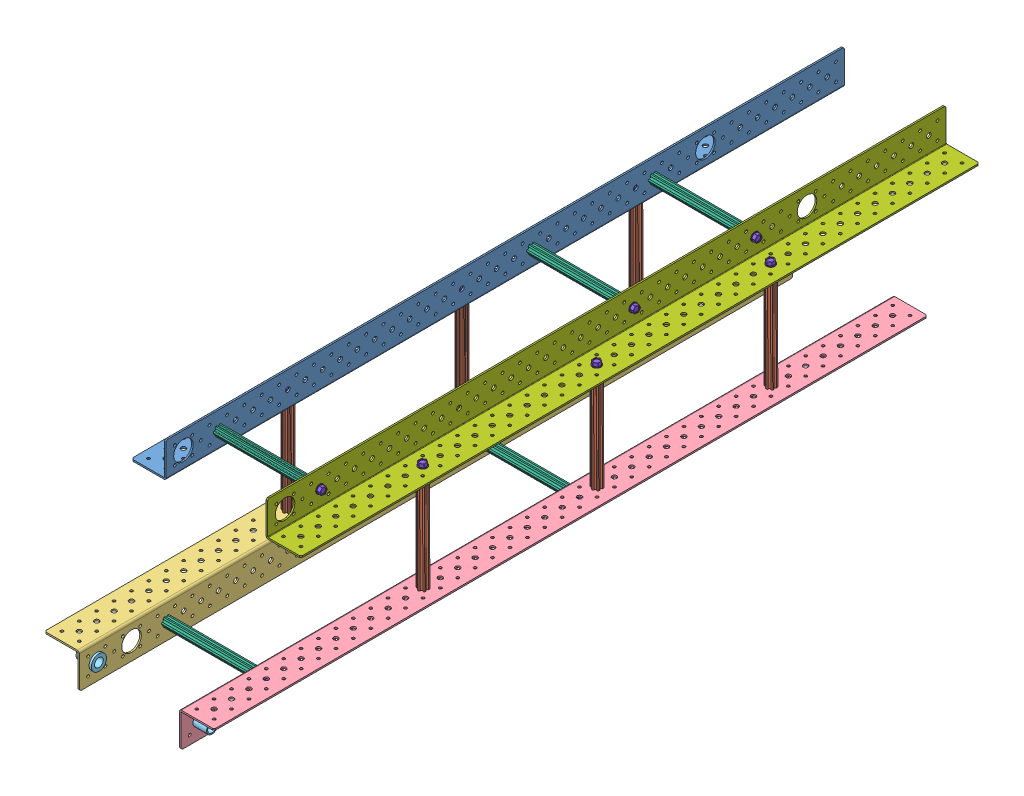
SolidWorks assembly intakePIPE, configuration Default. Lengths in mm.
Overall size (247.65 256.5 1117.26).
39 component instances, 8 part files, 96 mates.
Components (placement in the parent):
- 32inchMODIFIED-2: 32inchMODIFIED [Default] at (206.0968 622.2033 557.3996) x (0 0.999997 0.002241) z (0 -0.002241 0.999997) size (50.8 50.8 990.6)
- am-churro 500 churro tube MODIFIED-1: am-churro 500 churro tube MODIFIED [Default] at (180.6968 317.3187 594.8165) x (0 -0.002241 0.999997) z (0 0.999997 0.002241) size (14.66 12.7 152.4)
- am-churro 500 churro tube MODIFIED-2: am-churro 500 churro tube MODIFIED [Default] at (180.6968 773.3792 1103.8398) x (0 -0.002241 0.999997) z (0 -0.999997 -0.002241) size (14.66 12.7 152.4)
- am-churro 500 churro tube MODIFIED-3: am-churro 500 churro tube MODIFIED [Default] at (377.5468 773.3792 1103.8398) x (0.866025 0.00112 -0.499999) z (0 -0.999997 -0.002241) size (14.66 12.7 152.4)
- am-churro 500 churro tube MODIFIED-4: am-churro 500 churro tube MODIFIED [Default] at (377.5468 774.5176 595.8411) x (0.866025 0.00112 -0.499999) z (0 -0.999997 -0.002241) size (14.66 12.7 152.4)
- 32inchMODIFIED_BOTTOM-1: 32inchMODIFIED_BOTTOM [Default] at (206.0968 468.4946 1141.2567) x (0 -0.999997 -0.002241) z (0 0.002241 -0.999997) size (50.8 50.8 1041.4)
- 32inchMODIFIED_BOTTOM_2-1: 32inchMODIFIED_BOTTOM_2 [Default] at (352.1468 469.5191 684.0578) x (0 -0.999997 -0.002241) z (0 -0.002241 0.999997) size (50.8 50.8 1041.4)
- bushing1-1: bushing1 [Default] at (209.2718 442.497 1407.8991) x (0 0.579882 -0.8147) z (-1 0 0) size (22.26 22.26 25.4)
- bushing1-2: bushing1 [Default] at (348.9718 442.497 1407.8991) x (0 0.875683 0.482886) z (1 0 0) size (22.26 22.26 25.4)
- am-churro 500 churro tube MODIFIED-5: am-churro 500 churro tube MODIFIED [Default] at (377.5468 773.9484 849.8404) x (0 -0.002241 0.999997) z (0 -0.999997 -0.002241) size (14.66 12.7 152.4)
- am-churro 500 churro tube MODIFIED-6: am-churro 500 churro tube MODIFIED [Default] at (180.6968 773.9484 849.8404) x (0.866025 -0.00112 0.499999) z (0 -0.999997 -0.002241) size (14.66 12.7 152.4)
- am-churro 500 churro tube MODIFIED_5_5-1: am-churro 500 churro tube MODIFIED_5_5 [Default] at (47.3468 646.0949 1230.5549) x (0 0.864903 0.501939) z (1 0 0) size (14.66 12.7 146.05)
- am-churro 500 churro tube MODIFIED_5_5-2: am-churro 500 churro tube MODIFIED_5_5 [Default] at (47.3468 443.7492 849.1005) x (0 0.002241 -0.999997) z (1 0 0) size (14.66 12.7 146.05)
- am-churro 500 churro tube MODIFIED_5_5-3: am-churro 500 churro tube MODIFIED_5_5 [Default] at (510.8968 442.7247 1306.2993) x (0 0.002241 -0.999997) z (-1 0 0) size (14.66 12.7 146.05)
- 32inchMODIFIED_TOP2-3: 32inchMODIFIED_TOP2 [Default] at (352.1468 620.7804 1192.398) x (0 0.999997 0.002241) z (0 0.002241 -0.999997) size (50.8 50.8 990.6)
- am-churro 500 churro tube MODIFIED_5_5-4: am-churro 500 churro tube MODIFIED_5_5 [Default] at (47.3468 647.5179 595.5565) x (0 0.002241 -0.999997) z (1 0 0) size (14.66 12.7 146.05)
- am-churro 500 churro tube MODIFIED_5_5-5: am-churro 500 churro tube MODIFIED_5_5 [Default] at (47.3468 647.1195 773.356) x (0 0 -1) z (1 0 0) size (14.66 12.7 146.05)
- FHTS 0.25-20-0.75-1: FHTS 0.25-20-0.75 [FHTS 0.25-20-G-0.75-C] at (354.4328 647.5179 595.5565) x (-1 0 0) z (0 0.924225 0.381849) size (19.05 6.35 6.35)
- FHTS 0.25-20-0.75-2: FHTS 0.25-20-0.75 [FHTS 0.25-20-G-0.75-C] at (377.5468 624.4039 595.5047) x (0 -0.999997 -0.002241) z (0.002241 -0.002241 0.999995) size (19.05 6.35 6.35)
- FHTS 0.25-20-0.75-3: FHTS 0.25-20-0.75 [FHTS 0.25-20-G-0.75-C] at (354.4328 647.1195 773.356) x (-1 0 0) z (0 0.924225 0.381849) size (19.05 6.35 6.35)
- FHTS 0.25-20-0.75-4: FHTS 0.25-20-0.75 [FHTS 0.25-20-G-0.75-C] at (377.5468 623.8348 849.504) x (0 -0.999997 -0.002241) z (0.002241 -0.002241 0.999995) size (19.05 6.35 6.35)
- FHTS 0.25-20-0.75-5: FHTS 0.25-20-0.75 [FHTS 0.25-20-G-0.75-C] at (354.4328 646.0949 1230.5549) x (-1 0 0) z (0 0.924225 0.381849) size (19.05 6.35 6.35)
- FHTS 0.25-20-0.75-6: FHTS 0.25-20-0.75 [FHTS 0.25-20-G-0.75-C] at (377.5468 623.2656 1103.5034) x (0 -0.999997 -0.002241) z (0.002241 -0.002241 0.999995) size (19.05 6.35 6.35)
- FHTS 0.25-20-0.75-7: FHTS 0.25-20-0.75 [FHTS 0.25-20-G-0.75-C] at (354.4328 442.7247 1306.2993) x (-1 0 0) z (0 0.924225 0.381849) size (19.05 6.35 6.35)
- FHTS 0.25-20-0.75-8: FHTS 0.25-20-0.75 [FHTS 0.25-20-G-0.75-C] at (377.5468 466.294 1103.1516) x (0 0.999997 0.002241) z (-0.002241 -0.002241 0.999995) size (19.05 6.35 6.35)
- FHTS 0.25-20-0.75-9: FHTS 0.25-20-0.75 [FHTS 0.25-20-G-0.75-C] at (377.5468 466.8632 849.1523) x (0 0.999997 0.002241) z (-0.002241 -0.002241 0.999995) size (19.05 6.35 6.35)
- FHTS 0.25-20-0.75-10: FHTS 0.25-20-0.75 [FHTS 0.25-20-G-0.75-C] at (354.4328 443.7492 849.1005) x (-1 0 0) z (0 0.924225 0.381849) size (19.05 6.35 6.35)
- FHTS 0.25-20-0.75-11: FHTS 0.25-20-0.75 [FHTS 0.25-20-G-0.75-C] at (377.5468 467.4323 595.1529) x (0 0.999997 0.002241) z (-0.002241 -0.002241 0.999995) size (19.05 6.35 6.35)
- FHTS 0.25-20-0.75-12: FHTS 0.25-20-0.75 [FHTS 0.25-20-G-0.75-C] at (180.6968 466.294 1103.1516) x (0 0.999997 0.002241) z (-0.002241 -0.002241 0.999995) size (19.05 6.35 6.35)
- FHTS 0.25-20-0.75-13: FHTS 0.25-20-0.75 [FHTS 0.25-20-G-0.75-C] at (203.8108 442.7247 1306.2993) size (19.05 6.35 6.35)
- FHTS 0.25-20-0.75-14: FHTS 0.25-20-0.75 [FHTS 0.25-20-G-0.75-C] at (203.8108 443.7492 849.1005) size (19.05 6.35 6.35)
- FHTS 0.25-20-0.75-15: FHTS 0.25-20-0.75 [FHTS 0.25-20-G-0.75-C] at (180.6968 466.8632 849.1523) x (0 0.999997 0.002241) z (-0.002241 -0.002241 0.999995) size (19.05 6.35 6.35)
- FHTS 0.25-20-0.75-16: FHTS 0.25-20-0.75 [FHTS 0.25-20-G-0.75-C] at (180.6968 467.4323 595.1529) x (0 0.999997 0.002241) z (-0.002241 -0.002241 0.999995) size (19.05 6.35 6.35)
- FHTS 0.25-20-0.75-17: FHTS 0.25-20-0.75 [FHTS 0.25-20-G-0.75-C] at (203.8108 646.0949 1230.5549) size (19.05 6.35 6.35)
- FHTS 0.25-20-0.75-18: FHTS 0.25-20-0.75 [FHTS 0.25-20-G-0.75-C] at (180.6968 623.2656 1103.5034) x (0 -0.999997 -0.002241) z (0.002241 -0.002241 0.999995) size (19.05 6.35 6.35)
- FHTS 0.25-20-0.75-19: FHTS 0.25-20-0.75 [FHTS 0.25-20-G-0.75-C] at (180.6968 623.8348 849.504) x (0 -0.999997 -0.002241) z (0.002241 -0.002241 0.999995) size (19.05 6.35 6.35)
- FHTS 0.25-20-0.75-20: FHTS 0.25-20-0.75 [FHTS 0.25-20-G-0.75-C] at (203.8108 647.1195 773.356) size (19.05 6.35 6.35)
- FHTS 0.25-20-0.75-21: FHTS 0.25-20-0.75 [FHTS 0.25-20-G-0.75-C] at (180.6968 624.4039 595.5047) x (0 -0.999997 -0.002241) z (0.002241 -0.002241 0.999995) size (19.05 6.35 6.35)
- FHTS 0.25-20-0.75-22: FHTS 0.25-20-0.75 [FHTS 0.25-20-G-0.75-C] at (203.8108 647.5179 595.5565) size (19.05 6.35 6.35)
Mates (geometry in assembly coordinates):
- Parallel3: parallel anti-aligned: plane of 32inchMODIFIED_BOTTOM-1 through (206.0968 466.8155 1890.5548) normal (1 0 0); plane of 32inchMODIFIED_BOTTOM_2-1 through (352.1468 471.1982 -65.2403) normal (-1 0 0)
- Parallel4: parallel anti-aligned: plane of 32inchMODIFIED-2 through (206.0968 623.8824 -191.8985) normal (0 -0.999997 -0.002241); plane of 32inchMODIFIED_BOTTOM-1 through (206.0968 466.8155 1890.5548) normal (0 0.999997 0.002241)
- Coincident509: coincident anti-aligned: plane of 32inchMODIFIED-2 through (206.0968 623.8824 -191.8985) normal (0 -0.999997 -0.002241); plane of am-churro 500 churro tube MODIFIED-1 through (183.8718 622.1056 600.9988) normal (0 0.999997 0.002241)
- Coincident510: coincident anti-aligned: plane of am-churro 500 churro tube MODIFIED-1 through (171.8068 469.7183 595.158) normal (0 -0.999997 -0.002241); plane of 32inchMODIFIED_BOTTOM-1 through (206.0968 466.8155 1890.5548) normal (0 0.999997 0.002241)
- Coincident512: coincident anti-aligned: plane of am-churro 500 churro tube MODIFIED-4 through (383.8968 469.7183 595.158) normal (0 -0.999997 -0.002241); plane of 32inchMODIFIED_BOTTOM_2-1 through (352.1468 471.1982 -65.2403) normal (0 0.999997 0.002241)
- Parallel6: parallel aligned: plane of am-churro 500 churro tube MODIFIED-1 through (174.3468 622.1144 597.087) normal (-1 0 0); plane of 32inchMODIFIED_BOTTOM-1 through (155.2968 466.8155 1890.5548) normal (-1 0 0)
- Parallel7: parallel aligned: plane of am-churro 500 churro tube MODIFIED-4 through (383.8968 469.7148 596.7455) normal (1 0 0); plane of 32inchMODIFIED_BOTTOM_2-1 through (402.9468 471.1982 -65.2403) normal (1 0 0)
- Concentric513: concentric anti-aligned: cylinder of 32inchMODIFIED_BOTTOM-1 through (246.508 442.6109 1357.0992) axis (-1 0 0) radius 14.2875; cylinder of 32inchMODIFIED_BOTTOM_2-1 through (311.7357 442.6109 1357.0992) axis (1 0 0) radius 14.2875
- Concentric514: concentric anti-aligned: cylinder of 32inchMODIFIED_BOTTOM_2-1 through (311.7357 442.497 1407.8991) axis (1 0 0) radius 7.9693; cylinder of bushing1-2 through (374.3718 442.497 1407.8991) axis (-1 0 0) radius 7.9693
- Coincident518: coincident anti-aligned: plane of 32inchMODIFIED_BOTTOM_2-1 through (352.1468 471.1982 -65.2403) normal (-1 0 0); plane of bushing1-2 through (352.1468 442.497 1407.8991) normal (1 0 0)
- Concentric515: concentric anti-aligned: cylinder of 32inchMODIFIED_BOTTOM-1 through (246.508 442.497 1407.8991) axis (-1 0 0) radius 7.9693; cylinder of bushing1-1 through (183.8718 442.497 1407.8991) axis (1 0 0) radius 7.9693
- Coincident519: coincident anti-aligned: plane of 32inchMODIFIED_BOTTOM-1 through (206.0968 466.8155 1890.5548) normal (1 0 0); plane of bushing1-1 through (206.0968 442.497 1407.8991) normal (-1 0 0)
- Coincident520: coincident anti-aligned: plane of am-churro 500 churro tube MODIFIED-3 through (383.8968 468.58 1103.1568) normal (0 -0.999997 -0.002241); plane of 32inchMODIFIED_BOTTOM_2-1 through (352.1468 471.1982 -65.2403) normal (0 0.999997 0.002241)
- Coincident522: coincident anti-aligned: plane of am-churro 500 churro tube MODIFIED-2 through (177.5218 468.5676 1108.656) normal (0 -0.999997 -0.002241); plane of 32inchMODIFIED_BOTTOM-1 through (206.0968 466.8155 1890.5548) normal (0 0.999997 0.002241)
- Coincident523: coincident anti-aligned: plane of 32inchMODIFIED-2 through (206.0968 623.8824 -191.8985) normal (0 -0.999997 -0.002241); plane of am-churro 500 churro tube MODIFIED-2 through (189.5868 620.9796 1103.4983) normal (0 0.999997 0.002241)
- Coincident524: coincident anti-aligned: plane of 32inchMODIFIED_BOTTOM-1 through (206.0968 466.8155 1890.5548) normal (0 0.999997 0.002241); plane of am-churro 500 churro tube MODIFIED-6 through (183.8718 469.1368 854.6567) normal (0 -0.999997 -0.002241)
- Coincident525: coincident anti-aligned: plane of 32inchMODIFIED-2 through (206.0968 623.8824 -191.8985) normal (0 -0.999997 -0.002241); plane of am-churro 500 churro tube MODIFIED-6 through (185.1418 621.566 841.8) normal (0 0.999997 0.002241)
- Parallel8: parallel aligned: plane of 32inchMODIFIED_BOTTOM-1 through (155.2968 466.8155 1890.5548) normal (-1 0 0); plane of am-churro 500 churro tube MODIFIED-6 through (174.3468 469.1409 852.8236) normal (-1 0 0)
- Parallel9: parallel aligned: plane of am-churro 500 churro tube MODIFIED-2 through (174.3468 468.5718 1106.8229) normal (-1 0 0); plane of 32inchMODIFIED_BOTTOM-1 through (155.2968 466.8155 1890.5548) normal (-1 0 0)
- Parallel10: parallel aligned: plane of am-churro 500 churro tube MODIFIED-3 through (383.8968 468.5882 1099.4906) normal (1 0 0); plane of 32inchMODIFIED_BOTTOM_2-1 through (402.9468 471.1982 -65.2403) normal (1 0 0)
- Coincident529: coincident anti-aligned: plane of 32inchMODIFIED_BOTTOM_2-1 through (352.1468 471.1982 -65.2403) normal (-1 0 0); plane of am-churro 500 churro tube MODIFIED_5_5-3 through (352.1468 451.6147 1306.3193) normal (1 0 0)
- Coincident530: coincident anti-aligned: plane of 32inchMODIFIED_BOTTOM-1 through (206.0968 466.8155 1890.5548) normal (1 0 0); plane of am-churro 500 churro tube MODIFIED_5_5-3 through (206.0968 439.562 1300.793) normal (-1 0 0)
- Parallel11: parallel aligned: plane of 32inchMODIFIED_BOTTOM-1 through (203.8108 416.0157 1890.441) normal (0 -0.999997 -0.002241); plane of am-churro 500 churro tube MODIFIED_5_5-3 through (206.0968 436.3829 1302.6189) normal (0 -0.999997 -0.002241)
- Coincident532: coincident anti-aligned: plane of 32inchMODIFIED_BOTTOM_2-1 through (352.1468 471.1982 -65.2403) normal (0 0.999997 0.002241); plane of am-churro 500 churro tube MODIFIED-5 through (374.3718 469.1368 854.6567) normal (0 -0.999997 -0.002241)
- Parallel12: parallel aligned: plane of 32inchMODIFIED_BOTTOM_2-1 through (402.9468 471.1982 -65.2403) normal (1 0 0); plane of am-churro 500 churro tube MODIFIED-5 through (383.8968 469.1574 845.4912) normal (1 0 0)
- Coincident535: coincident anti-aligned: plane of 32inchMODIFIED-2 through (206.0968 623.8824 -191.8985) normal (1 0 0); plane of am-churro 500 churro tube MODIFIED_5_5-1 through (206.0968 650.5572 1222.8659) normal (-1 0 0)
- Coincident536: coincident anti-aligned: plane of 32inchMODIFIED_BOTTOM-1 through (206.0968 466.8155 1890.5548) normal (1 0 0); plane of am-churro 500 churro tube MODIFIED_5_5-2 through (206.0968 434.8592 849.0806) normal (-1 0 0)
- Coincident537: coincident anti-aligned: plane of 32inchMODIFIED_BOTTOM_2-1 through (352.1468 471.1982 -65.2403) normal (-1 0 0); plane of am-churro 500 churro tube MODIFIED_5_5-2 through (352.1468 446.9365 843.6084) normal (1 0 0)
- Parallel13: parallel aligned: plane of 32inchMODIFIED_BOTTOM_2-1 through (352.1468 471.1982 -65.2403) normal (0 0.999997 0.002241); plane of am-churro 500 churro tube MODIFIED_5_5-2 through (352.1468 450.1074 845.4486) normal (0 0.999997 0.002241)
- Concentric530: concentric anti-aligned: cylinder of 32inchMODIFIED-2 through (246.508 647.6886 519.3567) axis (-1 0 0) radius 14.2875; cylinder of 32inchMODIFIED_TOP2-3 through (349.3528 647.6886 519.3567) axis (1 0 0) radius 14.2875
- Coincident5553: coincident anti-aligned: plane of am-churro 500 churro tube MODIFIED-5 through (386.4368 621.5488 849.4989) normal (0 0.999997 0.002241); plane of 32inchMODIFIED_TOP2-3 through (352.1468 619.1013 1941.6962) normal (0 -0.999997 -0.002241)
- Concentric5533: concentric anti-aligned: cylinder of 32inchMODIFIED_BOTTOM-1 through (246.508 444.4891 518.9013) axis (-1 0 0) radius 14.2875; cylinder of 32inchMODIFIED_BOTTOM_2-1 through (311.7357 444.4891 518.9013) axis (1 0 0) radius 14.2875
- Parallel15: parallel aligned: plane of 32inchMODIFIED-2 through (203.8108 674.6822 -191.7846) normal (0 0.999997 0.002241); plane of am-churro 500 churro tube MODIFIED_5_5-4 through (352.1468 653.8643 597.1582) normal (0 0.999997 0.002241)
- Coincident5554: coincident aligned: plane of 32inchMODIFIED_BOTTOM_2-1 through (352.1468 471.1982 -65.2403) normal (-1 0 0); plane of 32inchMODIFIED_TOP2-3 through (352.1468 619.1013 1941.6962) normal (-1 0 0)
- Coincident5555: coincident aligned: plane of 32inchMODIFIED-2 through (206.0968 623.8824 -191.8985) normal (0 -0.999997 -0.002241); plane of 32inchMODIFIED_TOP2-3 through (352.1468 619.1013 1941.6962) normal (0 -0.999997 -0.002241)
- Concentric5534: concentric anti-aligned: cylinder of 32inchMODIFIED_BOTTOM_2-1 through (377.5468 577.3308 519.199) axis (0 -0.999997 -0.002241) radius 3.429; cylinder of 32inchMODIFIED_TOP2-3 through (377.5468 619.4947 519.2935) axis (0 0.999997 0.002241) radius 3.429
- Concentric5535: concentric anti-aligned: cylinder of 32inchMODIFIED-2 through (180.6968 612.59 519.278) axis (0 0.999997 0.002241) radius 3.429; cylinder of 32inchMODIFIED_BOTTOM-1 through (180.6968 696.2025 519.4654) axis (0 -0.999997 -0.002241) radius 3.429
- Concentric5536: concentric anti-aligned: cylinder of 32inchMODIFIED-2 through (246.508 645.9811 1281.3547) axis (-1 0 0) radius 14.2875; cylinder of 32inchMODIFIED_TOP2-3 through (311.7357 645.9811 1281.3547) axis (1 0 0) radius 14.2875
- Concentric5537: concentric aligned: cylinder of am-churro 500 churro tube MODIFIED-3 through (377.5468 468.58 1103.1568) axis (0 0.999997 0.002241) radius 2.9337; cylinder of 32inchMODIFIED_TOP2-3 through (377.5468 618.1856 1103.492) axis (0 0.999997 0.002241) radius 3.429
- Concentric5538: concentric aligned: cylinder of 32inchMODIFIED-2 through (180.6968 618.1856 1103.492) axis (0 0.999997 0.002241) radius 3.429; cylinder of am-churro 500 churro tube MODIFIED-2 through (180.6968 468.58 1103.1568) axis (0 0.999997 0.002241) radius 2.9337
- Concentric5539: concentric anti-aligned: cylinder of 32inchMODIFIED_BOTTOM-1 through (432.4108 442.7247 1306.2993) axis (-1 0 0) radius 3.429; cylinder of am-churro 500 churro tube MODIFIED_5_5-3 through (206.0968 442.7247 1306.2993) axis (1 0 0) radius 2.9337
- Concentric5540: concentric anti-aligned: cylinder of 32inchMODIFIED-2 through (180.6968 619.3239 595.4933) axis (0 0.999997 0.002241) radius 3.429; cylinder of am-churro 500 churro tube MODIFIED-1 through (180.6968 622.1179 595.4995) axis (0 -0.999997 -0.002241) radius 2.9337
- Concentric5541: concentric aligned: cylinder of am-churro 500 churro tube MODIFIED-4 through (377.5468 469.7183 595.158) axis (0 0.999997 0.002241) radius 2.9337; cylinder of 32inchMODIFIED_TOP2-3 through (377.5468 619.3239 595.4933) axis (0 0.999997 0.002241) radius 3.429
- Concentric5542: concentric aligned: cylinder of am-churro 500 churro tube MODIFIED-5 through (377.5468 469.1491 849.1574) axis (0 0.999997 0.002241) radius 2.9337; cylinder of 32inchMODIFIED_TOP2-3 through (377.5468 616.2148 849.487) axis (0 0.999997 0.002241) radius 3.429
- Concentric5543: concentric aligned: cylinder of 32inchMODIFIED-2 through (180.6968 618.7548 849.4926) axis (0 0.999997 0.002241) radius 3.429; cylinder of am-churro 500 churro tube MODIFIED-6 through (180.6968 469.1491 849.1574) axis (0 0.999997 0.002241) radius 2.9337
- Concentric5544: concentric aligned: cylinder of 32inchMODIFIED-2 through (246.508 646.0949 1230.5549) axis (-1 0 0) radius 3.429; cylinder of am-churro 500 churro tube MODIFIED_5_5-1 through (352.1468 646.0949 1230.5549) axis (-1 0 0) radius 2.9337
- Concentric5546: concentric aligned: cylinder of 32inchMODIFIED_BOTTOM-1 through (432.4108 443.7492 849.1005) axis (-1 0 0) radius 3.429; cylinder of am-churro 500 churro tube MODIFIED_5_5-2 through (352.1468 443.7492 849.1005) axis (-1 0 0) radius 2.9337
- Parallel16: parallel aligned: plane of 32inchMODIFIED-2 through (203.8108 674.6822 -191.7846) normal (0 0.999997 0.002241); plane of am-churro 500 churro tube MODIFIED_5_5-1 through (352.1468 652.4414 1232.1566) normal (0 0.999997 0.002241)
- Coincident5557: coincident anti-aligned: plane of 32inchMODIFIED-2 through (206.0968 623.8824 -191.8985) normal (1 0 0); plane of am-churro 500 churro tube MODIFIED_5_5-4 through (206.0968 638.6279 595.5365) normal (-1 0 0)
- Concentric5547: concentric anti-aligned: cylinder of 32inchMODIFIED_TOP2-3 through (349.3528 647.5179 595.5565) axis (1 0 0) radius 3.429; cylinder of am-churro 500 churro tube MODIFIED_5_5-4 through (352.1468 647.5179 595.5565) axis (-1 0 0) radius 2.9337
- Concentric5548: concentric aligned: cylinder of 32inchMODIFIED-2 through (208.8908 647.1195 773.356) axis (-1 0 0) radius 3.429; cylinder of am-churro 500 churro tube MODIFIED_5_5-5 through (352.1468 647.1195 773.356) axis (-1 0 0) radius 2.9337
- Coincident5558: coincident anti-aligned: plane of 32inchMODIFIED_TOP2-3 through (352.1468 619.1013 1941.6962) normal (-1 0 0); plane of am-churro 500 churro tube MODIFIED_5_5-5 through (352.1468 650.2945 767.8568) normal (1 0 0)
- Concentric55491: concentric aligned: cylinder of 32inchMODIFIED_TOP2-3 through (349.3528 647.5179 595.5565) axis (1 0 0) radius 3.429; cylinder of FHTS 0.25-20-0.75-1 through (354.4328 647.5179 595.5565) axis (1 0 0) radius 3.175
- Coincident55591: coincident anti-aligned: plane of 32inchMODIFIED_TOP2-3 through (354.4328 619.1013 1941.6962) normal (1 0 0); plane of FHTS 0.25-20-0.75-1 through (354.4328 646.3055 598.4909) normal (-1 0 0)
- Concentric55501: concentric aligned: cylinder of 32inchMODIFIED_TOP2-3 through (377.5468 619.3239 595.4933) axis (0 0.999997 0.002241) radius 3.429; cylinder of FHTS 0.25-20-0.75-2 through (377.5468 624.4039 595.5047) axis (0 0.999997 0.002241) radius 3.175
- Coincident55601: coincident anti-aligned: plane of 32inchMODIFIED_TOP2-3 through (352.1468 621.3873 1941.7013) normal (0 0.999997 0.002241); plane of FHTS 0.25-20-0.75-2 through (380.7218 624.4039 595.4976) normal (0 -0.999997 -0.002241)
- Concentric55511: concentric aligned: cylinder of 32inchMODIFIED_TOP2-3 through (349.3528 647.1195 773.356) axis (1 0 0) radius 3.429; cylinder of FHTS 0.25-20-0.75-3 through (354.4328 647.1195 773.356) axis (1 0 0) radius 3.175
- Coincident55611: coincident anti-aligned: plane of 32inchMODIFIED_TOP2-3 through (354.4328 619.1013 1941.6962) normal (1 0 0); plane of FHTS 0.25-20-0.75-3 through (354.4328 645.9071 776.2904) normal (-1 0 0)
- Concentric55521: concentric aligned: cylinder of 32inchMODIFIED_TOP2-3 through (377.5468 616.2148 849.487) axis (0 0.999997 0.002241) radius 3.429; cylinder of FHTS 0.25-20-0.75-4 through (377.5468 623.8348 849.504) axis (0 0.999997 0.002241) radius 3.175
- Coincident55621: coincident anti-aligned: plane of 32inchMODIFIED_TOP2-3 through (352.1468 621.3873 1941.7013) normal (0 0.999997 0.002241); plane of FHTS 0.25-20-0.75-4 through (380.7218 623.8348 849.4969) normal (0 -0.999997 -0.002241)
- Concentric55531: concentric aligned: cylinder of 32inchMODIFIED_TOP2-3 through (311.7357 646.0949 1230.5549) axis (1 0 0) radius 3.429; cylinder of FHTS 0.25-20-0.75-5 through (354.4328 646.0949 1230.5549) axis (1 0 0) radius 3.175
- Coincident55631: coincident anti-aligned: plane of 32inchMODIFIED_TOP2-3 through (354.4328 619.1013 1941.6962) normal (1 0 0); plane of FHTS 0.25-20-0.75-5 through (354.4328 644.8826 1233.4893) normal (-1 0 0)
- Concentric55541: concentric aligned: cylinder of 32inchMODIFIED_TOP2-3 through (377.5468 618.1856 1103.492) axis (0 0.999997 0.002241) radius 3.429; cylinder of FHTS 0.25-20-0.75-6 through (377.5468 623.2656 1103.5034) axis (0 0.999997 0.002241) radius 3.175
- Coincident55641: coincident anti-aligned: plane of 32inchMODIFIED_TOP2-3 through (352.1468 621.3873 1941.7013) normal (0 0.999997 0.002241); plane of FHTS 0.25-20-0.75-6 through (380.7218 623.2656 1103.4963) normal (0 -0.999997 -0.002241)
- Concentric55551: concentric aligned: cylinder of 32inchMODIFIED_BOTTOM_2-1 through (244.7048 442.7247 1306.2993) axis (1 0 0) radius 3.429; cylinder of FHTS 0.25-20-0.75-7 through (354.4328 442.7247 1306.2993) axis (1 0 0) radius 3.175
- Coincident55651: coincident anti-aligned: plane of 32inchMODIFIED_BOTTOM_2-1 through (354.4328 471.1982 -65.2403) normal (1 0 0); plane of FHTS 0.25-20-0.75-7 through (354.4328 441.5123 1309.2338) normal (-1 0 0)
- Concentric55561: concentric aligned: cylinder of 32inchMODIFIED_BOTTOM_2-1 through (377.5468 576.0217 1103.3975) axis (0 -0.999997 -0.002241) radius 3.429; cylinder of FHTS 0.25-20-0.75-8 through (377.5468 466.294 1103.1516) axis (0 -0.999997 -0.002241) radius 3.175
- Coincident55661: coincident anti-aligned: plane of 32inchMODIFIED_BOTTOM_2-1 through (352.1468 468.9122 -65.2454) normal (0 -0.999997 -0.002241); plane of FHTS 0.25-20-0.75-8 through (374.3718 466.294 1103.1445) normal (0 0.999997 0.002241)
- Concentric55571: concentric aligned: cylinder of 32inchMODIFIED_BOTTOM_2-1 through (377.5468 576.5909 849.3982) axis (0 -0.999997 -0.002241) radius 3.429; cylinder of FHTS 0.25-20-0.75-9 through (377.5468 466.8632 849.1523) axis (0 -0.999997 -0.002241) radius 3.175
- Coincident55671: coincident anti-aligned: plane of 32inchMODIFIED_BOTTOM_2-1 through (352.1468 468.9122 -65.2454) normal (0 -0.999997 -0.002241); plane of FHTS 0.25-20-0.75-9 through (374.3718 466.8632 849.1452) normal (0 0.999997 0.002241)
- Concentric55581: concentric aligned: cylinder of 32inchMODIFIED_BOTTOM_2-1 through (244.7048 443.7492 849.1005) axis (1 0 0) radius 3.429; cylinder of FHTS 0.25-20-0.75-10 through (354.4328 443.7492 849.1005) axis (1 0 0) radius 3.175
- Coincident55681: coincident anti-aligned: plane of 32inchMODIFIED_BOTTOM_2-1 through (354.4328 471.1982 -65.2403) normal (1 0 0); plane of FHTS 0.25-20-0.75-10 through (354.4328 442.5368 852.0349) normal (-1 0 0)
- Concentric55591: concentric aligned: cylinder of 32inchMODIFIED_BOTTOM_2-1 through (377.5468 577.16 595.3988) axis (0 -0.999997 -0.002241) radius 3.429; cylinder of FHTS 0.25-20-0.75-11 through (377.5468 467.4323 595.1529) axis (0 -0.999997 -0.002241) radius 3.175
- Coincident55691: coincident anti-aligned: plane of 32inchMODIFIED_BOTTOM_2-1 through (352.1468 468.9122 -65.2454) normal (0 -0.999997 -0.002241); plane of FHTS 0.25-20-0.75-11 through (374.3718 467.4323 595.1458) normal (0 0.999997 0.002241)
- Concentric55601: concentric aligned: cylinder of 32inchMODIFIED_BOTTOM-1 through (180.6968 694.8934 1103.6639) axis (0 -0.999997 -0.002241) radius 3.429; cylinder of FHTS 0.25-20-0.75-12 through (180.6968 466.294 1103.1516) axis (0 -0.999997 -0.002241) radius 3.175
- Coincident55701: coincident anti-aligned: plane of 32inchMODIFIED_BOTTOM-1 through (206.0968 464.5295 1890.5497) normal (0 -0.999997 -0.002241); plane of FHTS 0.25-20-0.75-12 through (177.5218 466.294 1103.1445) normal (0 0.999997 0.002241)
- Concentric55611: concentric aligned: cylinder of 32inchMODIFIED_BOTTOM-1 through (432.4108 442.7247 1306.2993) axis (-1 0 0) radius 3.429; cylinder of FHTS 0.25-20-0.75-13 through (203.8108 442.7247 1306.2993) axis (-1 0 0) radius 3.175
- Coincident55711: coincident anti-aligned: plane of 32inchMODIFIED_BOTTOM-1 through (203.8108 466.8155 1890.5548) normal (-1 0 0); plane of FHTS 0.25-20-0.75-13 through (203.8108 445.8997 1306.2993) normal (1 0 0)
- Concentric55621: concentric aligned: cylinder of 32inchMODIFIED_BOTTOM-1 through (432.4108 443.7492 849.1005) axis (-1 0 0) radius 3.429; cylinder of FHTS 0.25-20-0.75-14 through (203.8108 443.7492 849.1005) axis (-1 0 0) radius 3.175
- Coincident55721: coincident anti-aligned: plane of 32inchMODIFIED_BOTTOM-1 through (203.8108 466.8155 1890.5548) normal (-1 0 0); plane of FHTS 0.25-20-0.75-14 through (203.8108 446.9242 849.1005) normal (1 0 0)
- Concentric55631: concentric aligned: cylinder of 32inchMODIFIED_BOTTOM-1 through (180.6968 695.4626 849.6645) axis (0 -0.999997 -0.002241) radius 3.429; cylinder of FHTS 0.25-20-0.75-15 through (180.6968 466.8632 849.1523) axis (0 -0.999997 -0.002241) radius 3.175
- Coincident55731: coincident anti-aligned: plane of 32inchMODIFIED_BOTTOM-1 through (206.0968 464.5295 1890.5497) normal (0 -0.999997 -0.002241); plane of FHTS 0.25-20-0.75-15 through (177.5218 466.8632 849.1452) normal (0 0.999997 0.002241)
- Concentric55641: concentric aligned: cylinder of 32inchMODIFIED_BOTTOM-1 through (180.6968 696.0318 595.6652) axis (0 -0.999997 -0.002241) radius 3.429; cylinder of FHTS 0.25-20-0.75-16 through (180.6968 467.4323 595.1529) axis (0 -0.999997 -0.002241) radius 3.175
- Coincident55741: coincident anti-aligned: plane of 32inchMODIFIED_BOTTOM-1 through (206.0968 464.5295 1890.5497) normal (0 -0.999997 -0.002241); plane of FHTS 0.25-20-0.75-16 through (177.5218 467.4323 595.1458) normal (0 0.999997 0.002241)
- Concentric55651: concentric aligned: cylinder of 32inchMODIFIED-2 through (246.508 646.0949 1230.5549) axis (-1 0 0) radius 3.429; cylinder of FHTS 0.25-20-0.75-17 through (203.8108 646.0949 1230.5549) axis (-1 0 0) radius 3.175
- Coincident55751: coincident anti-aligned: plane of 32inchMODIFIED-2 through (203.8108 623.8824 -191.8985) normal (-1 0 0); plane of FHTS 0.25-20-0.75-17 through (203.8108 649.2699 1230.5549) normal (1 0 0)
- Concentric55661: concentric aligned: cylinder of 32inchMODIFIED-2 through (180.6968 618.1856 1103.492) axis (0 0.999997 0.002241) radius 3.429; cylinder of FHTS 0.25-20-0.75-18 through (180.6968 623.2656 1103.5034) axis (0 0.999997 0.002241) radius 3.175
- Coincident55761: coincident anti-aligned: plane of 32inchMODIFIED-2 through (206.0968 626.1684 -191.8934) normal (0 0.999997 0.002241); plane of FHTS 0.25-20-0.75-18 through (183.8718 623.2656 1103.4963) normal (0 -0.999997 -0.002241)
- Concentric55671: concentric aligned: cylinder of 32inchMODIFIED-2 through (180.6968 618.7548 849.4926) axis (0 0.999997 0.002241) radius 3.429; cylinder of FHTS 0.25-20-0.75-19 through (180.6968 623.8348 849.504) axis (0 0.999997 0.002241) radius 3.175
- Coincident55771: coincident anti-aligned: plane of 32inchMODIFIED-2 through (206.0968 626.1684 -191.8934) normal (0 0.999997 0.002241); plane of FHTS 0.25-20-0.75-19 through (183.8718 623.8348 849.4969) normal (0 -0.999997 -0.002241)
- Concentric55681: concentric aligned: cylinder of 32inchMODIFIED-2 through (208.8908 647.1195 773.356) axis (-1 0 0) radius 3.429; cylinder of FHTS 0.25-20-0.75-20 through (203.8108 647.1195 773.356) axis (-1 0 0) radius 3.175
- Coincident55781: coincident anti-aligned: plane of 32inchMODIFIED-2 through (203.8108 623.8824 -191.8985) normal (-1 0 0); plane of FHTS 0.25-20-0.75-20 through (203.8108 650.2945 773.356) normal (1 0 0)
- Concentric55691: concentric aligned: cylinder of 32inchMODIFIED-2 through (180.6968 619.3239 595.4933) axis (0 0.999997 0.002241) radius 3.429; cylinder of FHTS 0.25-20-0.75-21 through (180.6968 624.4039 595.5047) axis (0 0.999997 0.002241) radius 3.175
- Coincident55791: coincident anti-aligned: plane of 32inchMODIFIED-2 through (206.0968 626.1684 -191.8934) normal (0 0.999997 0.002241); plane of FHTS 0.25-20-0.75-21 through (183.8718 624.4039 595.4976) normal (0 -0.999997 -0.002241)
- Concentric55701: concentric aligned: cylinder of 32inchMODIFIED-2 through (208.8908 647.5179 595.5565) axis (-1 0 0) radius 3.429; cylinder of FHTS 0.25-20-0.75-22 through (203.8108 647.5179 595.5565) axis (-1 0 0) radius 3.175
- Coincident55801: coincident anti-aligned: plane of 32inchMODIFIED-2 through (203.8108 623.8824 -191.8985) normal (-1 0 0); plane of FHTS 0.25-20-0.75-22 through (203.8108 650.6929 595.5565) normal (1 0 0)
